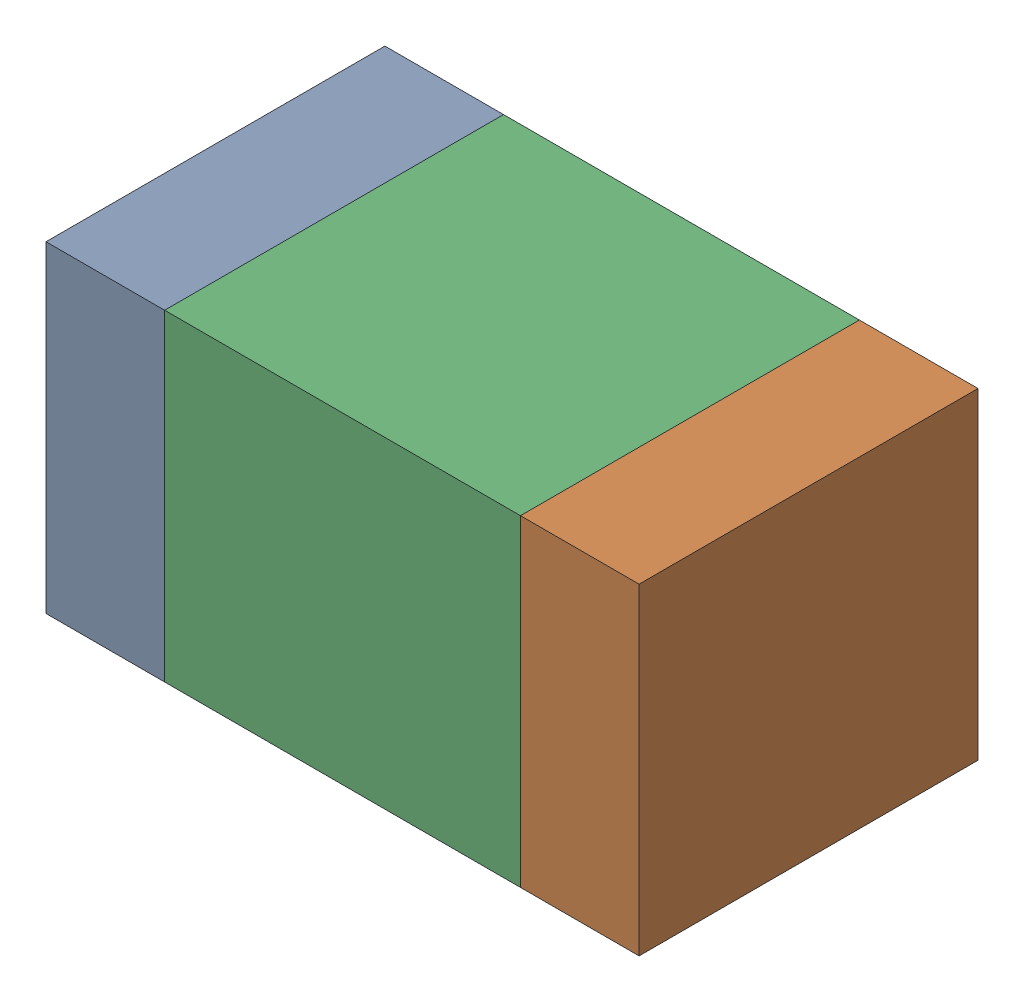
SolidWorks assembly C5, configuration Default. Lengths in mm.
Overall size (1.75 0.95 1).
6 component instances, 2 part files, 0 mates.
Components (placement in the parent):
- 959208936-1: 959208936 [Default] at (142.772 80.518 0) size (0.35 0.95 1)
  - Extruded-16-1: Extruded-16 [Default] at origin size (0.35 0.95 1)
- 959208936-2: 959208936 [Default] at (144.172 80.518 0) size (0.35 0.95 1)
  - Extruded-16-1: Extruded-16 [Default] at origin size (0.35 0.95 1)
- 959208800-1: 959208800 [Default] at (143.472 80.518 0) size (1.05 0.95 1)
  - Extruded-17-1: Extruded-17 [Default] at origin size (1.05 0.95 1)
